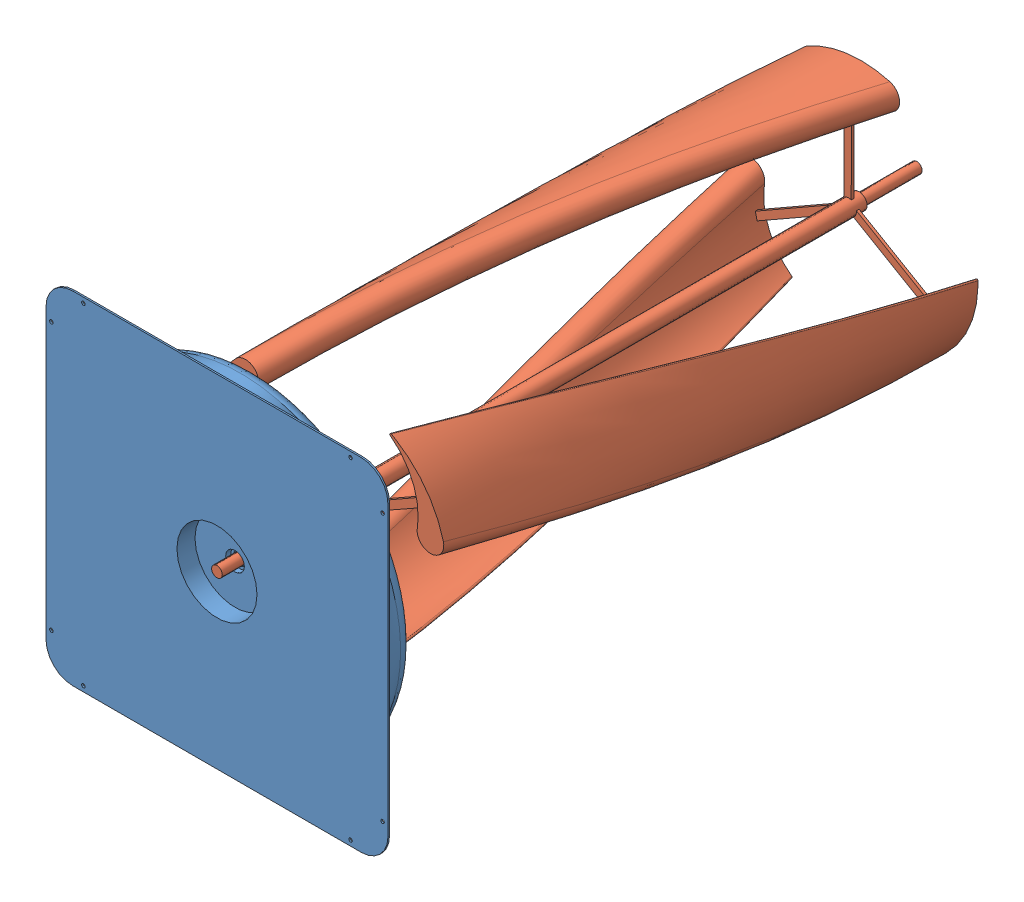
SolidWorks assembly Assem1, configuration Default. Lengths in mm.
Overall size (640 640 1310).
2 component instances, 2 part files, 2 mates.
Components (placement in the parent):
- VOET windturbine-1: VOET windturbine [Default] at (-56.9656 -2.7403 63.0922) size (640 640 150)
- wieken-1: wieken [Default] at (-56.9656 7.2597 106.9217) x (0 -1 0) z (1 0 0) size (478.85 1310 467.67)
Mates (geometry in assembly coordinates):
- Concentric1: concentric: cylinder of VOET windturbine-1 through (-56.9656 -2.7403 -43.0783) axis (0 0 -1) radius 12.5; cylinder of wieken-1 through (-56.9656 -2.7403 106.9217) axis (0 0 1) radius 10
- Coincident1: coincident: plane of VOET windturbine-1 through (213.0344 -272.7403 106.9217) normal (0 0 1); plane of wieken-1 through (-56.9656 7.2597 106.9217) normal (0 0 1)
